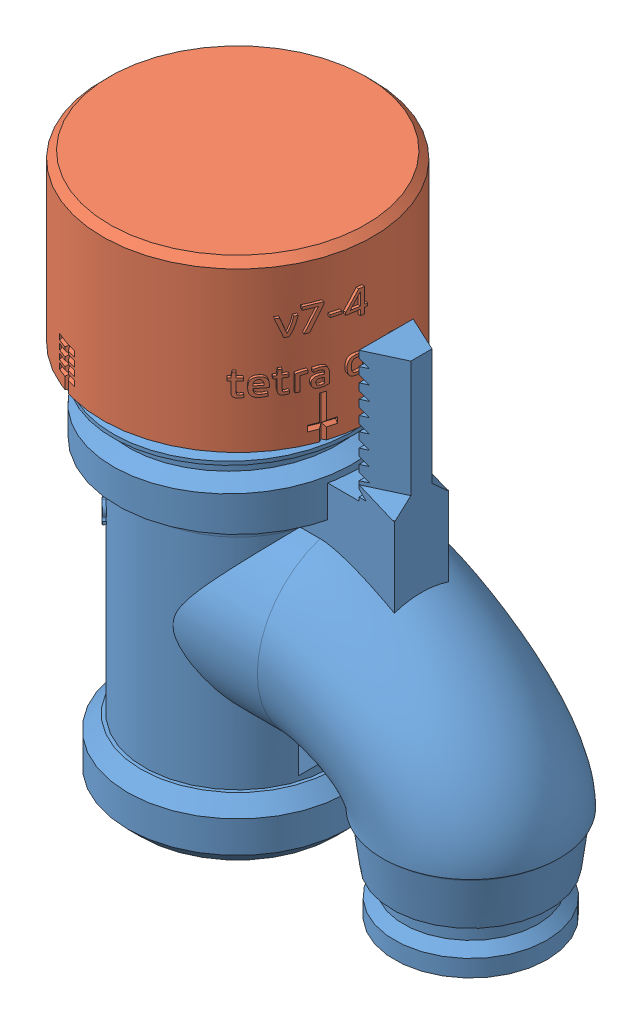
SolidWorks assembly tetra_concept-v7-4, configuration Default. Lengths in mm.
Overall size (69.76 77.35 48.62).
2 component instances, 2 part files, 1 mates.
Components (placement in the parent):
- tetra_concept-body-v7-4-1: tetra_concept-body-v7-4 [v7-4] at origin size (63.48 66.67 34.06)
- tetra_cap_v7-4-1: tetra_cap_v7-4 [v7-4] at (0 59.0656 0) x (-0.317885 0 0.948129) z (0.948129 0 0.317885) size (38.3 49.5 38.71)
Mates (geometry in assembly coordinates):
- Concentric1: concentric: cylinder of tetra_concept-body-v7-4-1 through (0 -20.0457 0) axis (0 -1 0) radius 8.825; cylinder of tetra_cap_v7-4-1 through (0 9.5656 0) axis (0 1 0) radius 8.8
